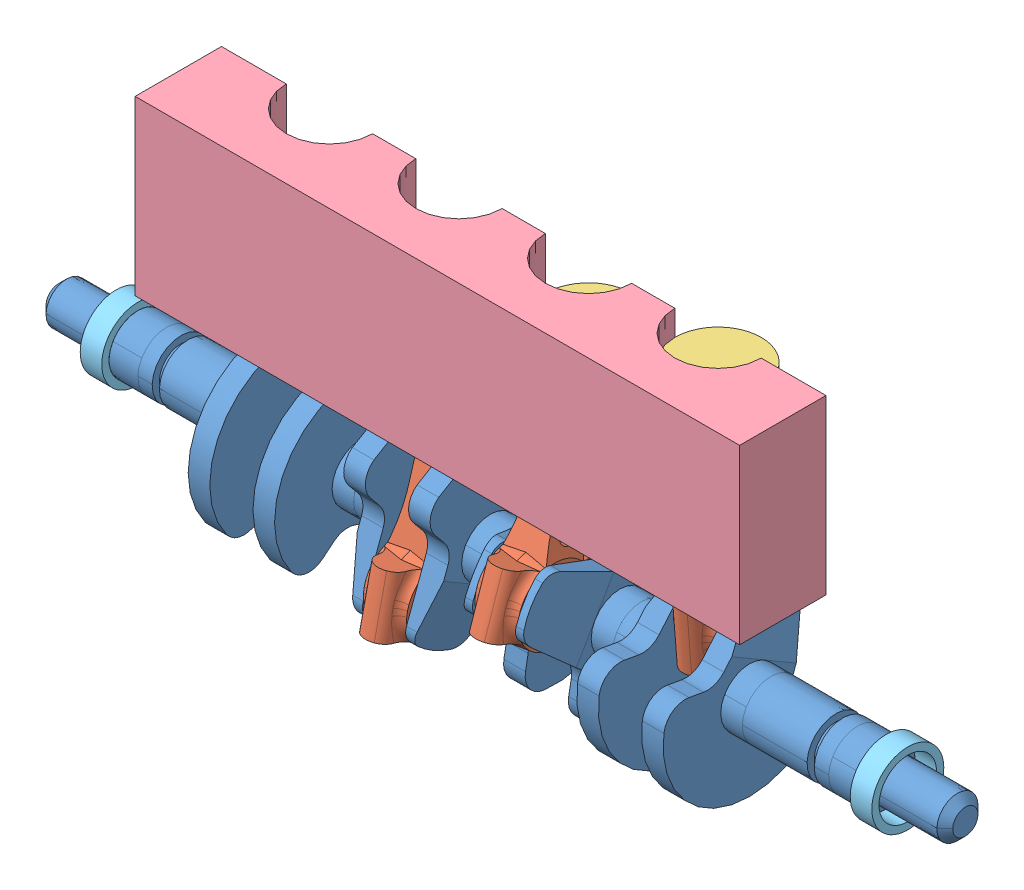
SolidWorks assembly Assem1, configuration Default. Lengths in mm.
Overall size (630 281.94 164.22).
12 component instances, 5 part files, 25 mates.
Components (placement in the parent):
- Part4.stp-1: Part4.stp [Default] at (-32.3977 32.0115 646.9844) x (1 0 0) z (0 -0.862681 0.505749) size (630 120.01 120.01)
- Part2.stp-1: Part2.stp [Default] at (-167.3977 14.3103 616.7906) x (1 0 0) z (0 0.982992 0.183646) size (31.32 75.41 167.5)
- Part2.stp-2: Part2.stp [Default] at (-77.3977 1.8177 664.6856) x (1 0 0) z (0 0.976508 -0.215479) size (31.32 75.41 167.5)
- Part2.stp-3: Part2.stp [Default] at (12.6023 49.7127 677.1783) x (1 0 0) z (0 0.947558 -0.319584) size (31.32 75.41 167.5)
- Part2.stp-4: Part2.stp [Default] at (102.6023 62.2053 629.2832) x (1 0 0) z (0 0.996832 0.079541) size (31.32 75.41 167.5)
- Part3.stp-1: Part3.stp [Default] at (102.6023 164.3251 638.8282) x (1 0 0) z (0 1 0) size (60.01 60.01 50)
- Part3.stp-2: Part3.stp [Default] at (-167.3977 114.7694 638.8282) x (1 0 0) z (0 1 0) size (60.01 60.01 50)
- Part3.stp-3: Part3.stp [Default] at (12.6023 145.9197 638.8282) x (1 0 0) z (0 1 0) size (60.01 60.01 50)
- Part3.stp-4: Part3.stp [Default] at (-77.3977 101.4987 638.8282) x (1 0 0) z (0 1 0) size (60.01 60.01 50)
- Part4-1: Part4 [Default] at (-32.3977 111.8451 668.8282) x (-1 0 0) z (0 0 -1) size (420 120 60)
- Part5-1: Part5 [Default] at (-307.3977 32.0115 646.9844) x (0 0 -1) z (1 0 0) size (50 50 15)
- Part5-2: Part5 [Default] at (227.6023 32.0115 646.9844) x (0 0 -1) z (1 0 0) size (50 50 15)
Mates (geometry in assembly coordinates):
- Concentric1: concentric aligned: cylinder of Part4.stp-1 through (-174.8977 2.4946 628.1762) axis (1 0 0) radius 20; cylinder of Part2.stp-1 through (-159.8977 2.4946 628.1762) axis (1 0 0) radius 20
- Width1: width aligned: plane of Part2.stp-1 through (-157.3977 2.4946 628.1762) normal (1 0 0); plane of Part2.stp-1 through (-177.3977 2.4946 628.1762) normal (-1 0 0); plane of Part4.stp-1 through (-182.3977 32.0115 646.9844) normal (1 0 0); plane of Part4.stp-1 through (-152.3977 32.0115 646.9844) normal (-1 0 0)
- Concentric2: concentric aligned: cylinder of Part4.stp-1 through (-84.8977 13.2033 676.5014) axis (1 0 0) radius 20; cylinder of Part2.stp-2 through (-69.8977 13.2033 676.5014) axis (1 0 0) radius 20
- Width2: width aligned: plane of Part2.stp-2 through (-67.3977 13.2033 676.5014) normal (1 0 0); plane of Part2.stp-2 through (-87.3977 13.2033 676.5014) normal (-1 0 0); plane of Part4.stp-1 through (-92.3977 32.0115 646.9844) normal (1 0 0); plane of Part4.stp-1 through (-62.3977 32.0115 646.9844) normal (-1 0 0)
- Concentric3: concentric aligned: cylinder of Part4.stp-1 through (5.1023 61.5284 665.7927) axis (1 0 0) radius 20; cylinder of Part2.stp-3 through (20.1023 61.5284 665.7927) axis (1 0 0) radius 20
- Width3: width aligned: plane of Part2.stp-3 through (2.6023 61.5284 665.7927) normal (-1 0 0); plane of Part2.stp-3 through (22.6023 61.5284 665.7927) normal (1 0 0); plane of Part4.stp-1 through (27.6023 32.0115 646.9844) normal (-1 0 0); plane of Part4.stp-1 through (-2.3977 32.0115 646.9844) normal (1 0 0)
- Concentric4: concentric aligned: cylinder of Part4.stp-1 through (95.1023 50.8197 617.4675) axis (1 0 0) radius 20; cylinder of Part2.stp-4 through (110.1023 50.8197 617.4675) axis (1 0 0) radius 20
- Width4: width anti-aligned: plane of Part2.stp-4 through (92.6023 50.8197 617.4675) normal (-1 0 0); plane of Part2.stp-4 through (112.6023 50.8197 617.4675) normal (1 0 0); plane of Part4.stp-1 through (87.6023 32.0115 646.9844) normal (1 0 0); plane of Part4.stp-1 through (117.6023 32.0115 646.9844) normal (-1 0 0)
- Concentric5: concentric aligned: cylinder of Part2.stp-4 through (107.6023 167.2971 646.3296) axis (1 0 0) radius 12.5; cylinder of Part3.stp-1 through (102.6023 167.2971 646.3296) axis (1 0 0) radius 12.5
- Width5: width aligned: plane of Part3.stp-1 through (82.6023 174.7971 646.3296) normal (-1 0 0); plane of Part3.stp-1 through (122.6023 174.7971 646.3296) normal (1 0 0); plane of Part2.stp-4 through (92.6023 50.8197 617.4675) normal (-1 0 0); plane of Part2.stp-4 through (112.6023 50.8197 617.4675) normal (1 0 0)
- Concentric6: concentric aligned: cylinder of Part2.stp-3 through (17.6023 179.9396 646.3296) axis (1 0 0) radius 12.5; cylinder of Part3.stp-3 through (12.6023 179.9396 646.3296) axis (1 0 0) radius 12.5
- Width6: width aligned: plane of Part3.stp-3 through (-7.3977 187.4396 646.3296) normal (-1 0 0); plane of Part3.stp-3 through (32.6023 187.4396 646.3296) normal (1 0 0); plane of Part2.stp-3 through (2.6023 61.5284 665.7927) normal (-1 0 0); plane of Part2.stp-3 through (22.6023 61.5284 665.7927) normal (1 0 0)
- Concentric7: concentric aligned: cylinder of Part2.stp-2 through (-72.3977 129.3483 646.3296) axis (1 0 0) radius 12.5; cylinder of Part3.stp-4 through (-77.3977 129.3483 646.3296) axis (1 0 0) radius 12.5
- Width7: width anti-aligned: plane of Part3.stp-4 through (-57.3977 136.8483 646.3296) normal (1 0 0); plane of Part3.stp-4 through (-97.3977 136.8483 646.3296) normal (-1 0 0); plane of Part2.stp-2 through (-87.3977 13.2033 676.5014) normal (-1 0 0); plane of Part2.stp-2 through (-67.3977 13.2033 676.5014) normal (1 0 0)
- Concentric8: concentric aligned: cylinder of Part2.stp-1 through (-162.3977 121.1135 646.3296) axis (1 0 0) radius 12.5; cylinder of Part3.stp-2 through (-167.3977 121.1135 646.3296) axis (1 0 0) radius 12.5
- Width8: width anti-aligned: plane of Part3.stp-2 through (-147.3977 128.6135 646.3296) normal (1 0 0); plane of Part3.stp-2 through (-187.3977 128.6135 646.3296) normal (-1 0 0); plane of Part2.stp-1 through (-177.3977 2.4946 628.1762) normal (-1 0 0); plane of Part2.stp-1 through (-157.3977 2.4946 628.1762) normal (1 0 0)
- Parallel1: parallel aligned: cylinder of Part3.stp-2 through (-167.3977 128.6135 646.3296) axis (0 -1 0) radius 30; cylinder of Part4-1 through (-167.3977 219.0463 646.3296) axis (0 -1 0) radius 30
- Concentric14: concentric anti-aligned: cylinder of Part4.stp-1 through (-32.3977 32.0115 646.9844) axis (1 0 0) radius 14.3112; cylinder of Part5-1 through (-292.3977 32.0115 646.9844) axis (-1 0 0) radius 20
- Coincident1: coincident anti-aligned: plane of Part4.stp-1 through (-292.3977 32.0115 646.9844) normal (-1 0 0); circle of Part5-1
- Concentric15: concentric anti-aligned: cylinder of Part4.stp-1 through (-32.3977 32.0115 646.9844) axis (1 0 0) radius 14.3112; cylinder of Part5-2 through (242.6023 32.0115 646.9844) axis (-1 0 0) radius 20
- Coincident2: coincident anti-aligned: plane of Part4.stp-1 through (227.6023 32.0115 646.9844) normal (1 0 0); plane of Part5-2 through (227.6023 32.0115 646.9844) normal (-1 0 0)
- Concentric16: concentric aligned: cylinder of Part3.stp-2 through (-167.3977 128.6135 646.3296) axis (0 -1 0) radius 30; cylinder of Part4-1 through (102.6023 219.0463 646.3296) axis (0 -1 0) radius 30
- Concentric17: concentric aligned: cylinder of Part3.stp-1 through (102.6023 174.7971 646.3296) axis (0 -1 0) radius 30; cylinder of Part4-1 through (-167.3977 219.0463 646.3296) axis (0 -1 0) radius 30
- Concentric18: concentric aligned: cylinder of Part3.stp-3 through (12.6023 187.4396 646.3296) axis (0 -1 0) radius 30; cylinder of Part4-1 through (-77.3977 219.0463 646.3296) axis (0 -1 0) radius 30
- Concentric19: concentric aligned: cylinder of Part3.stp-4 through (-77.3977 136.8483 646.3296) axis (0 -1 0) radius 30; cylinder of Part4-1 through (12.6023 219.0463 646.3296) axis (0 -1 0) radius 30
